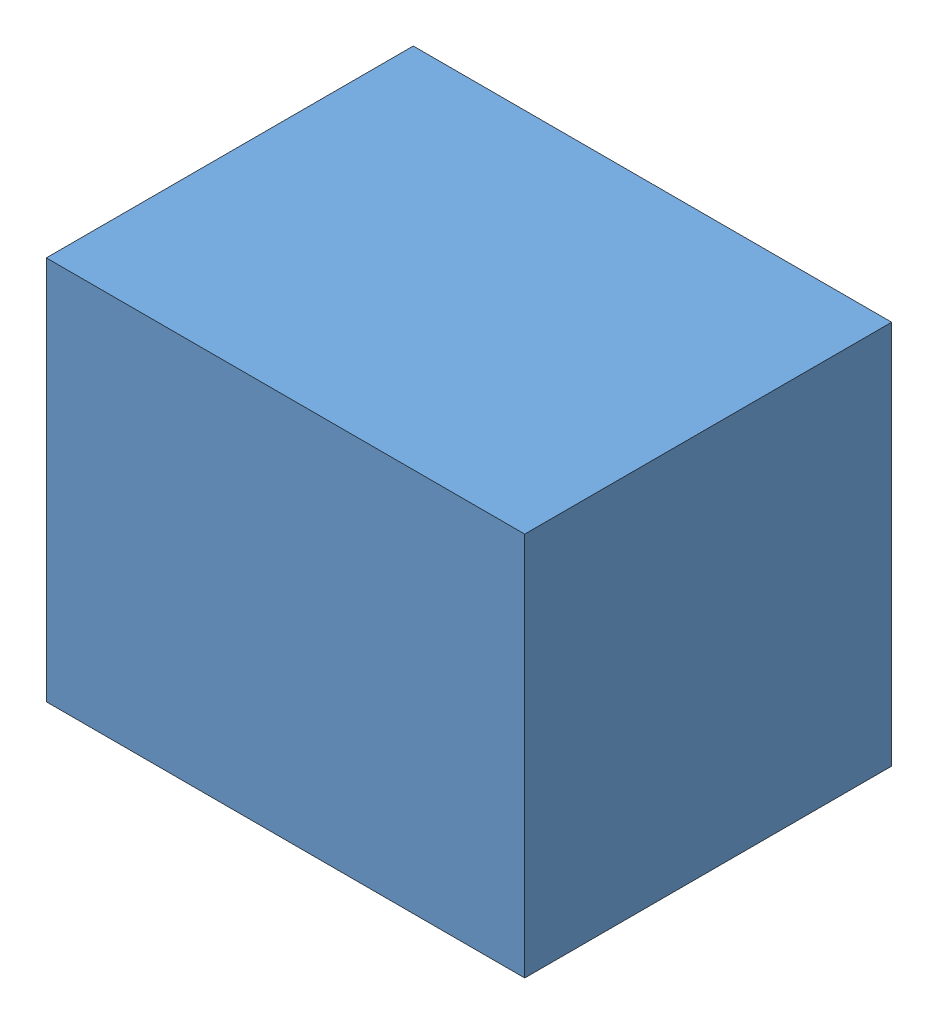
SolidWorks assembly enclosure, configuration Default. Lengths in mm.
Overall size (572.45 550.42 439.1).
2 component instances, 2 part files, 4 mates.
Components (placement in the parent):
- enclosure.bottom-1: enclosure.bottom [Default] at (64.9332 31.6396 99.319) x (0 0 -1) z (1 0 0) size (439.1 90.42 572.45)
- enclosure.top-1: enclosure.top [Default] at (64.9332 112.0596 99.319) x (0 0 -1) z (0 1 0) size (439.1 572.45 460)
Mates (geometry in assembly coordinates):
- InPlace1: in place: plane of enclosure.bottom-1 through (64.9332 112.0596 99.319) normal (0 1 0); plane of ? through (0 112.0596 0) normal (0 1 0); moOrthogonalPlaneRef_w of enclosure.bottom-1 through (64.9332 112.0596 99.319) normal (0 1 0); plane of ? through (0 112.0596 0) normal (0 0 -1); plane of enclosure.bottom-1 through (64.9332 112.0596 99.319) normal (0 1 0); line of ? through (-55 0 112.0596) axis (0 1 0); plane of enclosure.top-1 through (64.9332 112.0596 99.319) normal (0 1 0); unknown of enclosure.bottom-1
- Coincident1: coincident aligned: plane of enclosure.top-1; plane of ?
- Coincident2: coincident aligned: plane of enclosure.top-1; moOrthogonalPlaneRef_w of enclosure.bottom-1 through (64.9332 112.0596 99.319) normal (-1 0 0)
- Coincident3: coincident anti-aligned: plane of enclosure.top-1; moOrthogonalPlaneRef_w of enclosure.bottom-1 through (64.9332 112.0596 99.319) normal (0 0 1)
